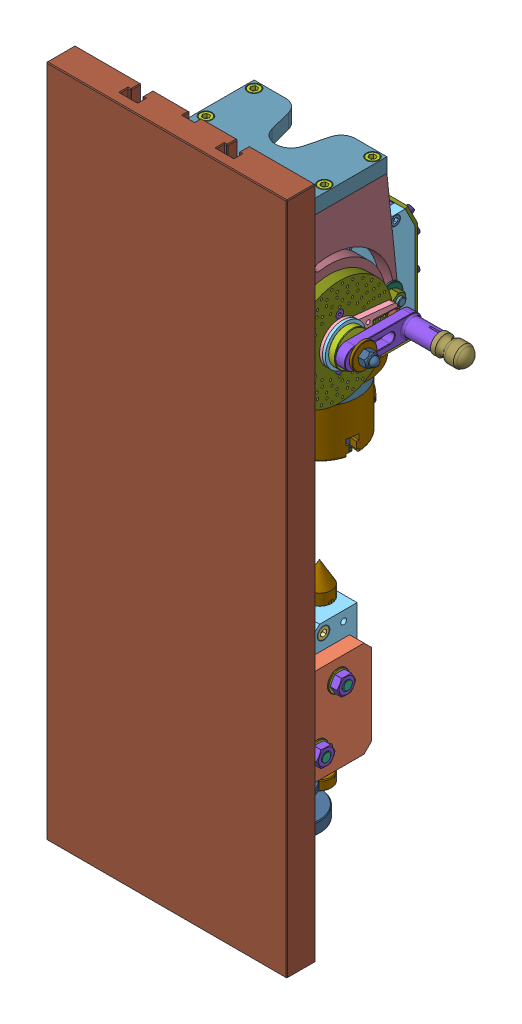
SolidWorks assembly Ensamblaje Divisor y punto., configuration Predeterminado. Lengths in mm.
Overall size (295 700 217.83).
168 component instances, 65 part files, 33 mates.
Components (placement in the parent):
- Ensamblaje Punto-1: Ensamblaje Punto [Predeterminado] at origin size (138 217 150)
  - Elemento 60 Base punto--1: Elemento 60 Base punto- [Predeterminado] at origin size (138 150 14.2)
  - Elemento 52 Lateral punto.-1: Elemento 52 Lateral punto. [Predeterminado] at (40 0 -64.5) x (0 0 1) z (-1 0 0) size (129 100 15)
  - Elemento 52 Lateral punto.-2: Elemento 52 Lateral punto. [Predeterminado] at (-25 0 -64.5) x (0 0 1) z (-1 0 0) size (129 100 15)
  - socket head cap screw_din-7: socket head cap screw_din [DIN 912 M8 x 25 --- 25N] at (32.5 -40 14.2) x (0 0 -1) z (0.338143 0.941095 0) size (33 13 13)
  - socket head cap screw_din-8: socket head cap screw_din [DIN 912 M8 x 25 --- 25N] at (32.5 0 14.2) x (0 0 -1) z (0.992882 0.119099 0) size (33 13 13)
  - socket head cap screw_din-9: socket head cap screw_din [DIN 912 M8 x 25 --- 25N] at (-32.5 -40 14.2) x (0 0 -1) z (-0.892203 0.451634 0) size (33 13 13)
  - socket head cap screw_din-10: socket head cap screw_din [DIN 912 M8 x 25 --- 25N] at (-32.5 0 14.2) x (0 0 -1) z (0.484607 -0.874732 0) size (33 13 13)
  - socket head cap screw_din-11: socket head cap screw_din [DIN 912 M8 x 25 --- 25N] at (-32.5 40 14.2) x (0 0 -1) z (-0.528458 0.848959 0) size (33 13 13)
  - socket head cap screw_din-12: socket head cap screw_din [DIN 912 M8 x 25 --- 25N] at (32.5 40 14.2) x (0 0 -1) z (0.979919 -0.199394 0) size (33 13 13)
  - Elemento 53 Guia del punto.-1: Elemento 53 Guia del punto. [Predeterminado] at (0 0 10.2) size (12 150 10)
  - Elemento 53 Guia del contrapunto.-1: Elemento 53 Guia del contrapunto. [Predeterminado] at (0 75 -129.8) x (0 -1 0) z (1 0 0) size (125 70 50)
  - socket head cap screw_din-13: socket head cap screw_din [DIN 912 M8 x 40 --- 28N] at (25 65 -94) x (-1 0 0) z (0 -0.924225 -0.381849) size (48 13 13)
  - Elemento 55 Esparrago contrapunto.-1: Elemento 55 Esparrago contrapunto. [Predeterminado] at (-50 30 -94) x (0 0.422146 -0.906528) z (1 0 0) size (10.26 10 101.48)
  - Elemento 55 Esparrago contrapunto.-2: Elemento 55 Esparrago contrapunto. [Predeterminado] at (50 -23.6 -72.6) x (0 0 1) z (-1 0 0) size (10.26 10 101.48)
  - Elemento 56 Arandela M-10-1: Elemento 56 Arandela M-10 [Predeterminado] at (41.2 -23.6 -72.6) x (0 0 1) z (-1 0 0) size (22 22 1.2)
  - Elemento 56 Arandela M-10-2: Elemento 56 Arandela M-10 [Predeterminado] at (41.2 30 -94) x (0 0 1) z (-1 0 0) size (22 22 1.2)
  - Elemento 56 Arandela M-10-3: Elemento 56 Arandela M-10 [Predeterminado] at (-41.2 30 -94) x (0 0 -1) z (1 0 0) size (22 22 1.2)
  - Elemento 56 Arandela M-10-4: Elemento 56 Arandela M-10 [Predeterminado] at (-41.2 -23.6 -72.6) x (0 0 -1) z (1 0 0) size (22 22 1.2)
  - Elemento 57 Tierca M-10-1: Elemento 57 Tierca M-10 [Default] at (-49.2 30 -94) x (0 0 -1) z (1 0 0) size (19.63 17 8)
  - Elemento 57 Tierca M-10-2: Elemento 57 Tierca M-10 [Default] at (-49.2 -23.6 -72.6) x (0 0 -1) z (1 0 0) size (19.63 17 8)
  - Elemento 57 Tierca M-10-3: Elemento 57 Tierca M-10 [Default] at (49.2 30 -94) x (0 0 1) z (-1 0 0) size (19.63 17 8)
  - Elemento 57 Tierca M-10-4: Elemento 57 Tierca M-10 [Default] at (49.2 -23.6 -72.6) x (0 0 1) z (-1 0 0) size (19.63 17 8)
  - Elemento 58 Punto.-1: Elemento 58 Punto. [Predeterminado] at (0 -91.6106 -114.8) x (0 0 -1) z (1 0 0) size (25 200 25)
  - Elemento 60 Tuerca de ajuste.-1: Elemento 60 Tuerca de ajuste. [Predeterminado] at (0 -108.6106 -84.8) x (0.982492 0 0.186307) z (-0.186307 0 0.982492) size (60 32 60)
  - Elemento 59 Husillo punto--1: Elemento 59 Husillo punto- [Predeterminado] at (0 -108.6106 -84.8) size (10.02 84.95 10.26)
- Ensamblaje Aparato divisor.-1: Ensamblaje Aparato divisor. [Predeterminado] at (0 418.6168 -0.8) x (-1 0 0) z (0 0 1) size (252 321.57 205.83)
  - Elemento 5 Base.-1: Elemento 5 Base. [Predeterminado] at origin size (138 220 15)
  - Elemento 7 Lateral.-1: Elemento 7 Lateral. [Predeterminado] at (-61.5 40 -55) x (0 -1 0) z (1 0 0) size (161 129.97 15)
  - Elemento 7 Lateral.-2: Elemento 7 Lateral. [Predeterminado] at (61.5 40 -55) x (0 -1 0) z (1 0 0) size (161 129.97 15)
  - Elemento 8 Trasera.-1: Elemento 8 Trasera. [Predeterminado] at (0 -78.5 -57.5) x (-1 0 0) z (0 1 0) size (138 115 15)
  - Elemento 1 Bisinfin.-1: Elemento 1 Bisinfin. [Predeterminado] at (-36.0756 40 -50) x (0 0 1) z (0 1 0) size (53.97 58 53.45)
  - Elemento 4 Disco división.-1: Elemento 4 Disco división. [Predeterminado] at (-79.5 40 -50) x (0 -1 0) z (0 0 1) size (110 11 110)
  - Elemento 2 Corona.-1: Elemento 2 Corona. [Predeterminado] at (0 25 -114) x (-0.605356 0 -0.795955) z (0 1 0) size (83.97 83.97 40)
  - Elemento 9 Arandela M 10-1: Elemento 9 Arandela M 10 [Default] at (-50 -98 0) x (-0.923728 -0.383049 0) z (0 0 -1) size (20 20 2)
  - Elemento 9 Arandela M 10-2: Elemento 9 Arandela M 10 [Default] at (50 -98 0) x (-0.923728 -0.383049 0) z (0 0 -1) size (20 20 2)
  - Elemento 9 Arandela M 10-3: Elemento 9 Arandela M 10 [Default] at (50 98 0) x (-0.923728 -0.383049 0) z (0 0 -1) size (20 20 2)
  - Elemento 9 Arandela M 10-4: Elemento 9 Arandela M 10 [Default] at (-50 98 0) x (-0.923728 -0.383049 0) z (0 0 -1) size (20 20 2)
  - Elemento 10 Tornillo M10-1: Elemento 10 Tornillo M10 [Default] at (50 -98 -2) x (0 0 1) z (-1 0 0) size (36.4 19.63 17)
  - Elemento 10 Tornillo M10-2: Elemento 10 Tornillo M10 [Default] at (-50 -98 -2) x (0 0 1) z (-1 0 0) size (36.4 19.63 17)
  - Elemento 10 Tornillo M10-3: Elemento 10 Tornillo M10 [Default] at (-50 98 -2) x (0 0 1) z (-1 0 0) size (36.4 19.63 17)
  - Elemento 10 Tornillo M10-4: Elemento 10 Tornillo M10 [Default] at (50 98 -2) x (0 0 1) z (-1 0 0) size (36.4 19.63 17)
  - Elemento 39 Tuerca cuadrada-1: Elemento 39 Tuerca cuadrada [Predeterminado] at (-50 98 17) x (0 -1 0) z (0 0 -1) size (15 18 16)
  - Elemento 39 Tuerca cuadrada-2: Elemento 39 Tuerca cuadrada [Predeterminado] at (50 98 17) x (0 -1 0) z (0 0 -1) size (15 18 16)
  - Elemento 39 Tuerca cuadrada-3: Elemento 39 Tuerca cuadrada [Predeterminado] at (50 -98 17) x (0 -1 0) z (0 0 -1) size (15 18 16)
  - Elemento 39 Tuerca cuadrada-4: Elemento 39 Tuerca cuadrada [Predeterminado] at (-50 -98 17) x (0 -1 0) z (0 0 -1) size (15 18 16)
  - Elemento 11 Tornillo giro.-1: Elemento 11 Tornillo giro. [Predeterminado] at (0 40 -55) x (0 1 0) z (-1 0 0) size (90 90 138)
  - Elemento 12 Soporte bis.-1: Elemento 12 Soporte bis. [Predeterminado] at (-69 40 -55) x (0 0 1) z (0 1 0) size (90 146 90)
  - Elemento 13 Oreja.-1: Elemento 13 Oreja. [Predeterminado] at (-48 40 -55) x (0 -1 0) z (1 0 0) size (109 158.5 12)
  - Elemento 16 Oreja 2-1: Elemento 16 Oreja 2 [Predeterminado] at (60 40 -55) x (0 -1 0) z (1 0 0) size (109 158.5 12)
  - Elemento 14 Tapa delantera.-1: Elemento 14 Tapa delantera. [Predeterminado] at (0 100.5 -107) x (1 0 0) z (0 1 0) size (108 104 12)
  - Elemento 15 Soporte trasero.-1: Elemento 15 Soporte trasero. [Predeterminado] at (0 -9.5 -114) x (0 0 1) z (0 -1 0) size (69.2 86 10)
  - Elemento 18 Soporte delantero.-1: Elemento 18 Soporte delantero. [Predeterminado] at (0 124.5 -114) x (-1 0 0) z (0 -1 0) size (100 95 33)
  - Elemento 17 Rodamiento 320007 J2 Q.-1: Elemento 17 Rodamiento 320007 J2 Q. [Default] at (0 17.5 -114) x (0 -1 0) z (-0.141258 0 0.989973) size (18 62 62)
    - rodamiento_-_32007_x_1_01-1: rodamiento_-_32007_x_1_01 [Default] at origin size (14 62 62)
    - rodamiento_-_32007_x_1_02-1: rodamiento_-_32007_x_1_02 [Default] at origin size (18 49.2 49.2)
    - rodamiento_-_32007_x_1_03-1: rodamiento_-_32007_x_1_03 [Default] at origin size (12.98 58.14 58.14)
  - Elemento 17 Rodamiento 320007 J2 Q.-2: Elemento 17 Rodamiento 320007 J2 Q. [Default] at (0 103.5 -114) x (0 1 0) z (0 0 1) size (18 62 62)
    - rodamiento_-_32007_x_1_01-1: rodamiento_-_32007_x_1_01 [Default] at origin size (14 62 62)
    - rodamiento_-_32007_x_1_02-1: rodamiento_-_32007_x_1_02 [Default] at origin size (18 49.2 49.2)
    - rodamiento_-_32007_x_1_03-1: rodamiento_-_32007_x_1_03 [Default] at origin size (12.98 58.14 58.14)
  - Elemento 19 Tapeta trasera.-1: Elemento 19 Tapeta trasera. [Predeterminado] at (0 21.5 -114) x (1 0 0) z (0 -1 0) size (75 75 27)
  - Elemento 20 Eje principal.-1: Elemento 20 Eje principal. [Predeterminado] at (0 147.5 -114) x (-0.795955 0 0.605356) z (0 -1 0) size (80 80 162)
  - Elemento 21 Arandela de ajuste.-1: Elemento 21 Arandela de ajuste. [Predeterminado] at (0 -5.5 -114) size (44 5 44)
  - Elemento 22 Techo^Ensamblaje Aparato divisor.-2: Elemento 22 Techo^Ensamblaje Aparato divisor. [Predeterminado] at origin size (108 122.34 13) (virtual)
  - Elemento 23 Eje sinfin.-1: Elemento 23 Eje sinfin. [Predeterminado] at (29 40 -50) x (0 -1 0) z (-1 0 0) size (25 27.8 162.1)
  - Elemento 3 Rodamiento 7304-1: Elemento 3 Rodamiento 7304 [Predeterminado] at (-44 40 -50) x (1 0 0) z (0 -0.200411 0.979712) size (36.1 52 52)
    - rodamiento_-_7304_be_1_01-1: rodamiento_-_7304_be_1_01 [Default] at origin size (15 52 52)
    - rodamiento_-_7304_be_1_02-1: rodamiento_-_7304_be_1_02 [Default] x (1 0 0) z (0 0.085608 0.996329) size (15 31.77 31.77)
    - Bolas rofamiento-1: Bolas rofamiento [Predeterminado] at (8 0 0) x (1 0 0) z (0 0.020733 -0.999785) size (36.1 45.27 45.63)
  - Elemento 3 Rodamiento 7304-2: Elemento 3 Rodamiento 7304 [Predeterminado] at (29 40 -50) x (1 0 0) z (0 -0.5536 0.832783) size (36.1 52 52)
    - rodamiento_-_7304_be_1_01-1: rodamiento_-_7304_be_1_01 [Default] at origin size (15 52 52)
    - rodamiento_-_7304_be_1_02-1: rodamiento_-_7304_be_1_02 [Default] x (1 0 0) z (0 0.085608 0.996329) size (15 31.77 31.77)
    - Bolas rofamiento-1: Bolas rofamiento [Predeterminado] at (8 0 0) x (1 0 0) z (0 0.020733 -0.999785) size (36.1 45.27 45.63)
  - Elemento 24 Soporte disco división.-1: Elemento 24 Soporte disco división. [Predeterminado] at (-69 40 -50) x (0 1 0) z (-1 0 0) size (80 80 15)
  - Elemento 26 Dedo 1.-1: Elemento 26 Dedo 1. [Predeterminado] at (-85 40 -50) x (0 0.998782 0.049348) z (-1 0 0) size (42 75.35 6)
  - Elemento 27 Dedo.-1: Elemento 27 Dedo. [Predeterminado] at (-85 40 -50) x (0 0.948231 0.317582) z (-1 0 0) size (42 74 6)
  - Elemento 28 DIN 3771-22.4x3,55-N-NBR 70.-1: Elemento 28 DIN 3771-22.4x3,55-N-NBR 70. [Predeterminado] at (-92.1672 40 -50) x (0 0.517314 0.855796) z (-1 0 0) size (27.1 27.1 2.4)
  - Elemento 29 Arandela dedos-1: Elemento 29 Arandela dedos [Predeterminado] at (-98 40 -50) x (0 0 -1) z (1 0 0) size (36 36 7)
  - Elemento 30 Manivela.-1: Elemento 30 Manivela. [Predeterminado] at (-108 40 -101.25) x (0 -1 0) z (1 0 0) size (22.2 80 40.06)
  - Elemento 31 Arandela manivela.-1: Elemento 31 Arandela manivela. [Predeterminado] at (-108 40 -50) x (0 0.064178 0.997938) z (-1 0 0) size (26 26 3)
  - Elemento 32 DIN 986 - M8-1: Elemento 32 DIN 986 - M8 [Predeterminado] at (-111 40 -50) x (-1 0 0) z (0 -0.924225 -0.381849) size (15.88 15.86 13)
  - Elemento 33 Eje tetón.-1: Elemento 33 Eje tetón. [Predeterminado] at (-148 40 -101.25) x (0 -0.054895 -0.998492) z (1 0 0) size (10 10 66)
  - Elemento 34 Pomo.-1: Elemento 34 Pomo. [Predeterminado] at (-154.3 40 -101.25) x (0 0.424982 0.905202) z (-1 0 0) size (21 21 32)
  - Elemento 35 Centraje.-1: Elemento 35 Centraje. [Predeterminado] at (0 90 16) x (1 0 0) z (0 1 0) size (12 10 40)
  - Elemento 35 Centraje.-2: Elemento 35 Centraje. [Predeterminado] at (0 0 16) x (1 0 0) z (0 1 0) size (12 10 40)
  - Elemento 35 Centraje.-3: Elemento 35 Centraje. [Predeterminado] at (0 -90 16) x (1 0 0) z (0 1 0) size (12 10 40)
  - Elemento 36 Esparrago.-1: Elemento 36 Esparrago. [Predeterminado] at (-62 40 -118) x (0 0 -1) z (1 0 0) size (8 8 40)
  - Elemento 36 Esparrago.-2: Elemento 36 Esparrago. [Predeterminado] at (62 40 -118) x (0 -0.693083 -0.720858) z (-1 0 0) size (8 8 40)
  - Elemento 37 Arandela DIN 9021-8.4-1: Elemento 37 Arandela DIN 9021-8.4 [Predeterminado] at (71 40 -118) x (-1 0 0) z (0 -0.924225 -0.381849) size (2 24 24)
  - Elemento 37 Arandela DIN 9021-8.4-2: Elemento 37 Arandela DIN 9021-8.4 [Predeterminado] at (-71 40 -118) size (2 24 24)
  - Elemento 38 AS 1112 M8 Tipo 5 Tuerca.-1: Elemento 38 AS 1112 M8 Tipo 5 Tuerca. [Predeterminado] at (71 40 -118) size (8 15.01 13)
  - Elemento 38 AS 1112 M8 Tipo 5 Tuerca.-2: Elemento 38 AS 1112 M8 Tipo 5 Tuerca. [Predeterminado] at (-71 40 -118) x (-1 0 0) z (0 -0.924225 -0.381849) size (8 15.01 13)
  - Elemento 41 DIN 912-M4x16-1: Elemento 41 DIN 912-M4x16 [Predeterminado] at (49 -6.0029 -156.6026) x (1 0 0) z (0 -0.447214 -0.894427) size (7 7 20)
  - Elemento 41 DIN 912-M4x16-2: Elemento 41 DIN 912-M4x16 [Predeterminado] at (49 49.5 -162) x (-0.923728 -0.383049 0) z (0 0 -1) size (7 7 20)
  - Elemento 41 DIN 912-M4x16-3: Elemento 41 DIN 912-M4x16 [Predeterminado] at (35 100.5 -162) x (-0.923728 -0.383049 0) z (0 0 -1) size (7 7 20)
  - Elemento 41 DIN 912-M4x16-4: Elemento 41 DIN 912-M4x16 [Predeterminado] at (-35 100.5 -162) x (-0.923728 -0.383049 0) z (0 0 -1) size (7 7 20)
  - Elemento 41 DIN 912-M4x16-5: Elemento 41 DIN 912-M4x16 [Predeterminado] at (-49 49.5 -162) x (-0.923728 -0.383049 0) z (0 0 -1) size (7 7 20)
  - Elemento 41 DIN 912-M4x16-6: Elemento 41 DIN 912-M4x16 [Predeterminado] at (-49 15.1 -162) x (-0.923728 -0.383049 0) z (0 0 -1) size (7 7 20)
  - Elemento 41 DIN 912-M4x16-7: Elemento 41 DIN 912-M4x16 [Predeterminado] at (-49 -6.0029 -156.6026) x (1 0 0) z (0 -0.447214 -0.894427) size (7 7 20)
  - Elemento 41 DIN 912-M4x16-8: Elemento 41 DIN 912-M4x16 [Predeterminado] at (49 15.1 -162) x (-0.923728 -0.383049 0) z (0 0 -1) size (7 7 20)
  - Elemento 46 DIN 912-M6x25-1: Elemento 46 DIN 912-M6x25 [Predeterminado] at (-21 118.5 -150.3731) x (1 0 0) z (0 1 0) size (10 10 30)
  - Elemento 46 DIN 912-M6x25-2: Elemento 46 DIN 912-M6x25 [Predeterminado] at (21 118.5 -150.3731) x (1 0 0) z (0 1 0) size (10 10 30)
  - Elemento 46 DIN 912-M6x25-3: Elemento 46 DIN 912-M6x25 [Predeterminado] at (-42 118.5 -114) x (1 0 0) z (0 1 0) size (10 10 30)
  - Elemento 46 DIN 912-M6x25-4: Elemento 46 DIN 912-M6x25 [Predeterminado] at (42 118.5 -114) x (1 0 0) z (0 1 0) size (10 10 30)
  - Elemento 46 DIN 912-M6x25-5: Elemento 46 DIN 912-M6x25 [Predeterminado] at (-21 118.5 -77.6269) x (1 0 0) z (0 1 0) size (10 10 30)
  - Elemento 46 DIN 912-M6x25-6: Elemento 46 DIN 912-M6x25 [Predeterminado] at (21 118.5 -77.6269) x (1 0 0) z (0 1 0) size (10 10 30)
  - Elemento 46 DIN 912-M6x25-7: Elemento 46 DIN 912-M6x25 [Predeterminado] at (-48.5 100.5 -151.5) x (1 0 0) z (0 1 0) size (10 10 30)
  - Elemento 46 DIN 912-M6x25-8: Elemento 46 DIN 912-M6x25 [Predeterminado] at (-48.5 100.5 -62.5) x (0.84739 0 -0.530971) z (0 1 0) size (10 10 30)
  - Elemento 46 DIN 912-M6x25-9: Elemento 46 DIN 912-M6x25 [Predeterminado] at (48.5 100.5 -62.5) x (1 0 0) z (0 1 0) size (10 10 30)
  - Elemento 46 DIN 912-M6x25-10: Elemento 46 DIN 912-M6x25 [Predeterminado] at (48.5 100.5 -151.5) x (1 0 0) z (0 1 0) size (10 10 30)
  - Elemento 50 DIN 912-M6x20-1: Elemento 50 DIN 912-M6x20 [Predeterminado] at (48 -9 -139) x (0 0 -1) z (1 0 0) size (10 10 26)
  - Elemento 50 DIN 912-M6x20-2: Elemento 50 DIN 912-M6x20 [Predeterminado] at (48 -9 -89) x (0 0 -1) z (1 0 0) size (10 10 26)
  - Elemento 50 DIN 912-M6x20-3: Elemento 50 DIN 912-M6x20 [Predeterminado] at (-48 -9 -89) x (0 0 1) z (-1 0 0) size (10 10 26)
  - Elemento 50 DIN 912-M6x20-4: Elemento 50 DIN 912-M6x20 [Predeterminado] at (-48 -9 -139) x (0 0 1) z (-1 0 0) size (10 10 26)
  - Elemento 44 DIN 912-M5x30-1: Elemento 44 DIN 912-M5x30 [Predeterminado] at (17.15 -9.5 -143.7047) x (1 0 0) z (0 -1 0) size (8.5 8.5 35)
  - Elemento 44 DIN 912-M5x30-2: Elemento 44 DIN 912-M5x30 [Predeterminado] at (34.3 -9.5 -114) x (1 0 0) z (0 -1 0) size (8.5 8.5 35)
  - Elemento 44 DIN 912-M5x30-3: Elemento 44 DIN 912-M5x30 [Predeterminado] at (17.15 -9.5 -84.2953) x (1 0 0) z (0 -1 0) size (8.5 8.5 35)
  - Elemento 44 DIN 912-M5x30-4: Elemento 44 DIN 912-M5x30 [Predeterminado] at (-34.3 -9.5 -114) x (1 0 0) z (0 -1 0) size (8.5 8.5 35)
  - Elemento 44 DIN 912-M5x30-5: Elemento 44 DIN 912-M5x30 [Predeterminado] at (-17.15 -9.5 -84.2953) x (1 0 0) z (0 -1 0) size (8.5 8.5 35)
  - Elemento 44 DIN 912-M5x30-6: Elemento 44 DIN 912-M5x30 [Predeterminado] at (-17.15 -9.5 -143.7047) x (1 0 0) z (0 -1 0) size (8.5 8.5 35)
  - Elemento 66 Tapeta posterior.-1: Elemento 66 Tapeta posterior. [Predeterminado] at (0 -14.5 -114) x (-1 0 0) z (0 0 1) size (63 6 63)
  - Elemento 42 ANSI B18.22M-4N-1: Elemento 42 ANSI B18.22M-4N [Predeterminado] at (21.6506 -20.5 -126.5) x (1 0 0) z (0 -1 0) size (8.25 8.25 16)
  - Elemento 42 ANSI B18.22M-4N-2: Elemento 42 ANSI B18.22M-4N [Predeterminado] at (0 -20.5 -89) x (1 0 0) z (0 -1 0) size (8.25 8.25 16)
  - Elemento 42 ANSI B18.22M-4N-3: Elemento 42 ANSI B18.22M-4N [Predeterminado] at (-21.6506 -20.5 -126.5) x (1 0 0) z (0 -1 0) size (8.25 8.25 16)
  - Elemento 43 DIN 912-M4x20.-1: Elemento 43 DIN 912-M4x20. [Predeterminado] at (77 40 -95) x (0 0 -1) z (1 0 0) size (7 7 24)
  - Elemento 43 DIN 912-M4x20.-2: Elemento 43 DIN 912-M4x20. [Predeterminado] at (77 74.641 -35) x (0 0 -1) z (1 0 0) size (7 7 24)
  - Elemento 43 DIN 912-M4x20.-3: Elemento 43 DIN 912-M4x20. [Predeterminado] at (77 5.359 -35) x (0 0 -1) z (1 0 0) size (7 7 24)
  - flat head screw_am-5: flat head screw_am [B18.6.7M - M4 x 0.7 x 20 Type I Cross Recessed FHMS --20N] at (0 -104 21) x (0 0 -1) z (1 0 0) size (20 8.4 8.4)
  - flat head screw_am-6: flat head screw_am [B18.6.7M - M4 x 0.7 x 20 Type I Cross Recessed FHMS --20N] at (0 -76 21) x (0 0 -1) z (1 0 0) size (20 8.4 8.4)
  - flat head screw_am-7: flat head screw_am [B18.6.7M - M4 x 0.7 x 20 Type I Cross Recessed FHMS --20N] at (0 -14 21) x (0 0 -1) z (1 0 0) size (20 8.4 8.4)
  - flat head screw_am-8: flat head screw_am [B18.6.7M - M4 x 0.7 x 20 Type I Cross Recessed FHMS --20N] at (0 14 21) x (0 0 -1) z (1 0 0) size (20 8.4 8.4)
  - flat head screw_am-9: flat head screw_am [B18.6.7M - M4 x 0.7 x 20 Type I Cross Recessed FHMS --20N] at (0 76 21) x (0 0 -1) z (1 0 0) size (20 8.4 8.4)
  - flat head screw_am-10: flat head screw_am [B18.6.7M - M4 x 0.7 x 20 Type I Cross Recessed FHMS --20N] at (0 104 21) x (0 0 -1) z (1 0 0) size (20 8.4 8.4)
  - socket head cap screw_am-2: socket head cap screw_am [B18.3.1M - 8 x 1.25 x 25 Hex SHCS -- 25NHX] at (61.5 -86 -107.5) x (0 1 0) z (0 0 1) size (33 13 13)
  - socket head cap screw_am-3: socket head cap screw_am [B18.3.1M - 8 x 1.25 x 25 Hex SHCS -- 25NHX] at (61.5 -86 -57.5) x (0 1 0) z (0 0 1) size (33 13 13)
  - socket head cap screw_am-4: socket head cap screw_am [B18.3.1M - 8 x 1.25 x 25 Hex SHCS -- 25NHX] at (61.5 -86 -7.5) x (0 1 0) z (0 0 1) size (33 13 13)
  - socket head cap screw_am-5: socket head cap screw_am [B18.3.1M - 8 x 1.25 x 25 Hex SHCS -- 25NHX] at (-61.5 -86 -57.5) x (0 1 0) z (0 0 1) size (33 13 13)
  - socket head cap screw_am-6: socket head cap screw_am [B18.3.1M - 8 x 1.25 x 25 Hex SHCS -- 25NHX] at (-61.5 -86 -7.5) x (0 1 0) z (0 0 1) size (33 13 13)
  - socket head cap screw_am-7: socket head cap screw_am [B18.3.1M - 8 x 1.25 x 25 Hex SHCS -- 25NHX] at (-61.5 -86 -107.5) x (0 1 0) z (0 0 1) size (33 13 13)
  - socket head cap screw_am-8: socket head cap screw_am [B18.3.1M - 8 x 1.25 x 25 Hex SHCS -- 25NHX] at (61.5 -35.1 15) x (0 0 -1) z (1 0 0) size (33 13 13)
  - socket head cap screw_am-9: socket head cap screw_am [B18.3.1M - 8 x 1.25 x 25 Hex SHCS -- 25NHX] at (61.5 23.7 15) x (0 0 -1) z (1 0 0) size (33 13 13)
  - socket head cap screw_am-10: socket head cap screw_am [B18.3.1M - 8 x 1.25 x 25 Hex SHCS -- 25NHX] at (61.5 82.5 15) x (0 0 -1) z (1 0 0) size (33 13 13)
  - socket head cap screw_am-11: socket head cap screw_am [B18.3.1M - 8 x 1.25 x 25 Hex SHCS -- 25NHX] at (-61.5 23.7 15) x (0 0 -1) z (1 0 0) size (33 13 13)
  - socket head cap screw_am-12: socket head cap screw_am [B18.3.1M - 8 x 1.25 x 25 Hex SHCS -- 25NHX] at (-61.5 -35.1 15) x (0 0 -1) z (1 0 0) size (33 13 13)
  - socket head cap screw_am-13: socket head cap screw_am [B18.3.1M - 8 x 1.25 x 25 Hex SHCS -- 25NHX] at (-34 -78.5 15) x (0 0 -1) z (1 0 0) size (33 13 13)
  - socket head cap screw_am-14: socket head cap screw_am [B18.3.1M - 8 x 1.25 x 25 Hex SHCS -- 25NHX] at (34 -78.5 15) x (0 0 -1) z (0.888604 -0.458675 0) size (33 13 13)
  - socket head cap screw_am-15: socket head cap screw_am [B18.3.1M - 8 x 1.25 x 25 Hex SHCS -- 25NHX] at (-61.5 82.5 15) x (0 0 -1) z (1 0 0) size (33 13 13) (hidden)
  - socket countersunk head screw_am-1: socket countersunk head screw_am [B18.3.5M - 4 x 0.7 x 20 Socket FCHS  -- 20N] at (-85 15 -50) size (20 7.8 7.8)
  - socket countersunk head screw_am-2: socket countersunk head screw_am [B18.3.5M - 4 x 0.7 x 20 Socket FCHS  -- 20N] at (-85 65 -50) size (20 7.8 7.8)
  - socket countersunk head screw_am-3: socket countersunk head screw_am [B18.3.5M - 4 x 0.7 x 20 Socket FCHS  -- 20N] at (-74 40 -85) size (20 7.8 7.8)
  - Elemento 6 Plato de garras.-1: Elemento 6 Plato de garras. [Predeterminado] at (0 144.5 -114) x (-0.605356 0 -0.795955) z (0 1 0) size (81 80 50.12)
  - Garra-1: Garra [Predeterminado] at (0 177.5 -114) x (0.386639 0 -0.922231) z (0.922231 0 0.386639) size (31.34 33 12)
  - Garra-2: Garra [Predeterminado] at (0 177.5 -114) x (0.605356 0 0.795955) z (-0.795955 0 0.605356) size (31.34 33 12)
  - Garra-3: Garra [Predeterminado] at (0 177.5 -114) x (-0.991995 0 0.126277) z (-0.126277 0 -0.991995) size (31.34 33 12)
- Elemento 9 Arandela M 10-1: Elemento 9 Arandela M 10 [Default] at (-50 63 0) x (-0.923728 -0.383049 0) z (0 0 -1) size (20 20 2)
- Elemento 9 Arandela M 10-2: Elemento 9 Arandela M 10 [Default] at (50 63 0) x (-0.923728 -0.383049 0) z (0 0 -1) size (20 20 2)
- Elemento 9 Arandela M 10-3: Elemento 9 Arandela M 10 [Default] at (-50 -63 0) x (-0.923728 -0.383049 0) z (0 0 -1) size (20 20 2)
- Elemento 9 Arandela M 10-4: Elemento 9 Arandela M 10 [Default] at (50 -63 0) x (-0.923728 -0.383049 0) z (0 0 -1) size (20 20 2)
- Elemento 10 Tornillo M10-1: Elemento 10 Tornillo M10 [Default] at (-50 63 -2) x (0 0 1) z (-1 0 0) size (36.4 19.63 17)
- Elemento 10 Tornillo M10-2: Elemento 10 Tornillo M10 [Default] at (50 63 0) x (0 0 1) z (-1 0 0) size (36.4 19.63 17)
- Elemento 10 Tornillo M10-3: Elemento 10 Tornillo M10 [Default] at (50 -63 -2) x (0 0 1) z (-1 0 0) size (36.4 19.63 17)
- Elemento 10 Tornillo M10-4: Elemento 10 Tornillo M10 [Default] at (-50 -63 -2) x (0 0 1) z (-1 0 0) size (36.4 19.63 17)
- Elemento 39 Tuerca cuadrada-1: Elemento 39 Tuerca cuadrada [Predeterminado] at (50 -63 16.2) x (0 -1 0) z (0 0 -1) size (15 18 16)
- Elemento 39 Tuerca cuadrada-2: Elemento 39 Tuerca cuadrada [Predeterminado] at (50 63 16.2) x (0 -1 0) z (0 0 -1) size (15 18 16)
- Elemento 39 Tuerca cuadrada-3: Elemento 39 Tuerca cuadrada [Predeterminado] at (-50 63 16.2) x (0 -1 0) z (0 0 -1) size (15 18 16)
- Elemento 39 Tuerca cuadrada-4: Elemento 39 Tuerca cuadrada [Predeterminado] at (-50 -63 16.2) x (0 -1 0) z (0 0 -1) size (15 18 16)
- Bancada.-1: Bancada. [Predeterminado] at (0 -127.0053 29.2) x (1 0 0) z (0 1 0) size (250 30 700)
Mates (geometry in assembly coordinates):
- Concéntrica2: concentric aligned: cylinder of Ensamblaje Punto-1/Elemento 58 Punto.-1 through (0 108.3894 -114.8) axis (0 1 0) radius 12.5; cylinder of Ensamblaje Aparato divisor.-1/Elemento 6 Plato de garras.-1 through (0 224.1168 -114.8) axis (0 1 0) radius 40
- Coincidente2: coincident aligned: plane of Ensamblaje Punto-1/Elemento 60 Base punto--1 through (-50 -63 14.2) normal (0 0 1); plane of Ensamblaje Aparato divisor.-1/Elemento 5 Base.-1 through (69 308.6168 14.2) normal (0 0 1)
- Concéntrica3: concentric anti-aligned: cylinder of Ensamblaje Punto-1/Elemento 60 Base punto--1 through (50 -63 14.2) axis (0 0 -1) radius 6; cylinder of Elemento 9 Arandela M 10-4 through (50 -63 0) axis (0 0 1) radius 5.25
- Coincidente3: coincident anti-aligned: plane of Ensamblaje Punto-1/Elemento 60 Base punto--1 through (-50 -63 0) normal (0 0 -1); plane of Elemento 9 Arandela M 10-4 through (45.1504 -65.011 0) normal (0 0 1)
- Concéntrica4: concentric anti-aligned: cylinder of Ensamblaje Punto-1/Elemento 60 Base punto--1 through (-50 -63 14.2) axis (0 0 -1) radius 6; cylinder of Elemento 9 Arandela M 10-3 through (-50 -63 0) axis (0 0 1) radius 10
- Coincidente4: coincident anti-aligned: plane of Ensamblaje Punto-1/Elemento 60 Base punto--1 through (-50 -63 0) normal (0 0 -1); plane of Elemento 9 Arandela M 10-3 through (-54.8496 -65.011 0) normal (0 0 1)
- Concéntrica5: concentric anti-aligned: cylinder of Ensamblaje Punto-1/Elemento 60 Base punto--1 through (50 63 14.2) axis (0 0 -1) radius 6; cylinder of Elemento 9 Arandela M 10-2 through (50 63 0) axis (0 0 1) radius 5.25
- Coincidente5: coincident anti-aligned: plane of Ensamblaje Punto-1/Elemento 60 Base punto--1 through (-50 -63 0) normal (0 0 -1); plane of Elemento 9 Arandela M 10-2 through (45.1504 60.989 0) normal (0 0 1)
- Concéntrica6: concentric anti-aligned: cylinder of Ensamblaje Punto-1/Elemento 60 Base punto--1 through (-50 63 14.2) axis (0 0 -1) radius 6; cylinder of Elemento 9 Arandela M 10-1 through (-50 63 0) axis (0 0 1) radius 5.25
- Coincidente6: coincident anti-aligned: plane of Ensamblaje Punto-1/Elemento 60 Base punto--1 through (-50 -63 0) normal (0 0 -1); plane of Elemento 9 Arandela M 10-1 through (-54.8496 60.989 0) normal (0 0 1)
- Concéntrica7: concentric anti-aligned: cylinder of Elemento 9 Arandela M 10-1 through (-50 63 0) axis (0 0 1) radius 5.25; cylinder of Elemento 10 Tornillo M10-1 through (-50 63 12.74) axis (0 0 -1) radius 5
- Coincidente7: coincident anti-aligned: plane of Elemento 9 Arandela M 10-1 through (-58.3136 59.5526 -2) normal (0 0 -1); plane of Elemento 10 Tornillo M10-1 through (-50 69.3575 -2) normal (0 0 1)
- Concéntrica8: concentric aligned: cylinder of Ensamblaje Punto-1/Elemento 60 Base punto--1 through (50 63 14.2) axis (0 0 -1) radius 6; cylinder of Elemento 10 Tornillo M10-2 through (50 63 14.74) axis (0 0 -1) radius 5
- Coincidente8: coincident anti-aligned: plane of Ensamblaje Punto-1/Elemento 60 Base punto--1 through (-50 -63 0) normal (0 0 -1); plane of Elemento 10 Tornillo M10-2 through (50 69.3575 0) normal (0 0 1)
- Concéntrica9: concentric aligned: cylinder of Ensamblaje Punto-1/Elemento 60 Base punto--1 through (50 -63 14.2) axis (0 0 -1) radius 6; cylinder of Elemento 10 Tornillo M10-3 through (50 -63 12.74) axis (0 0 -1) radius 5
- Coincidente9: coincident anti-aligned: plane of Elemento 9 Arandela M 10-4 through (41.6864 -66.4474 -2) normal (0 0 -1); plane of Elemento 10 Tornillo M10-3 through (50 -56.6425 -2) normal (0 0 1)
- Concéntrica10: concentric aligned: cylinder of Ensamblaje Punto-1/Elemento 60 Base punto--1 through (-50 -63 14.2) axis (0 0 -1) radius 6; cylinder of Elemento 10 Tornillo M10-4 through (-50 -63 12.74) axis (0 0 -1) radius 5
- Coincidente10: coincident anti-aligned: plane of Elemento 9 Arandela M 10-3 through (-58.3136 -66.4474 -2) normal (0 0 -1); plane of Elemento 10 Tornillo M10-4 through (-50 -56.6425 -2) normal (0 0 1)
- Concéntrica11: concentric anti-aligned: cylinder of Elemento 10 Tornillo M10-2 through (50 63 14.74) axis (0 0 -1) radius 5; cylinder of Elemento 39 Tuerca cuadrada-2 through (50 63 30.2) axis (0 0 1) radius 5
- Distancia1: distance = 10 mm anti-aligned: plane of Elemento 39 Tuerca cuadrada-2 through (56 48.7 24.2) normal (0 0 -1); plane of Ensamblaje Punto-1/Elemento 60 Base punto--1 through (-50 -63 14.2) normal (0 0 1)
- Paralelo1: parallel aligned: plane of Ensamblaje Aparato divisor.-1/Elemento 39 Tuerca cuadrada-2 through (-41 312.4168 16.2) normal (1 0 0); plane of Elemento 39 Tuerca cuadrada-2 through (59 72 30.2) normal (1 0 0)
- Concéntrica12: concentric anti-aligned: cylinder of Elemento 10 Tornillo M10-1 through (-50 63 12.74) axis (0 0 -1) radius 5; cylinder of Elemento 39 Tuerca cuadrada-3 through (-50 63 30.2) axis (0 0 1) radius 5
- Coincidente13: coincident aligned: plane of Elemento 39 Tuerca cuadrada-2 through (56 48.7 24.2) normal (0 0 -1); plane of Elemento 39 Tuerca cuadrada-3 through (-44 48.7 24.2) normal (0 0 -1)
- Paralelo2: parallel anti-aligned: plane of Elemento 39 Tuerca cuadrada-2 through (59 72 30.2) normal (1 0 0); plane of Elemento 39 Tuerca cuadrada-3 through (-59 71.2 16.2) normal (-1 0 0)
- Concéntrica13: concentric anti-aligned: cylinder of Elemento 10 Tornillo M10-3 through (50 -63 12.74) axis (0 0 -1) radius 5; cylinder of Elemento 39 Tuerca cuadrada-1 through (50 -63 30.2) axis (0 0 1) radius 5
- Coincidente15: coincident aligned: plane of Elemento 39 Tuerca cuadrada-1 through (41 -72 24.2) normal (0 0 -1); plane of Elemento 39 Tuerca cuadrada-2 through (56 48.7 24.2) normal (0 0 -1)
- Paralelo3: parallel anti-aligned: plane of Elemento 39 Tuerca cuadrada-1 through (41 -54.8 16.2) normal (-1 0 0); plane of Elemento 39 Tuerca cuadrada-2 through (59 72 30.2) normal (1 0 0)
- Concéntrica14: concentric anti-aligned: cylinder of Elemento 10 Tornillo M10-4 through (-50 -63 12.74) axis (0 0 -1) radius 5; cylinder of Elemento 39 Tuerca cuadrada-4 through (-50 -63 30.2) axis (0 0 1) radius 5
- Coincidente16: coincident aligned: plane of Elemento 39 Tuerca cuadrada-1 through (41 -91.6977 32.2) normal (0 0 1); plane of Elemento 39 Tuerca cuadrada-4 through (-59 -91.6977 32.2) normal (0 0 1)
- Paralelo4: parallel anti-aligned: plane of Elemento 39 Tuerca cuadrada-1 through (41 -54.8 16.2) normal (-1 0 0); plane of Elemento 39 Tuerca cuadrada-4 through (-41 -54 30.2) normal (1 0 0)
- Coincidente17: coincident anti-aligned: plane of Ensamblaje Aparato divisor.-1/Elemento 5 Base.-1 through (69 308.6168 14.2) normal (0 0 1); plane of Bancada.-1 through (125 572.9947 14.2) normal (0 0 -1)
- Coincidente18: coincident anti-aligned: plane of Ensamblaje Aparato divisor.-1/Elemento 39 Tuerca cuadrada-4 through (59 508.4168 16.2) normal (1 0 0); plane of Bancada.-1 through (59 -221.2053 25.17) normal (-1 0 0)
- Coincidente19: coincident anti-aligned: plane of Ensamblaje Aparato divisor.-1/Elemento 39 Tuerca cuadrada-3 through (-59 507.6168 30.2) normal (-1 0 0); plane of Bancada.-1 through (-59 -221.2053 25.17) normal (1 0 0)
